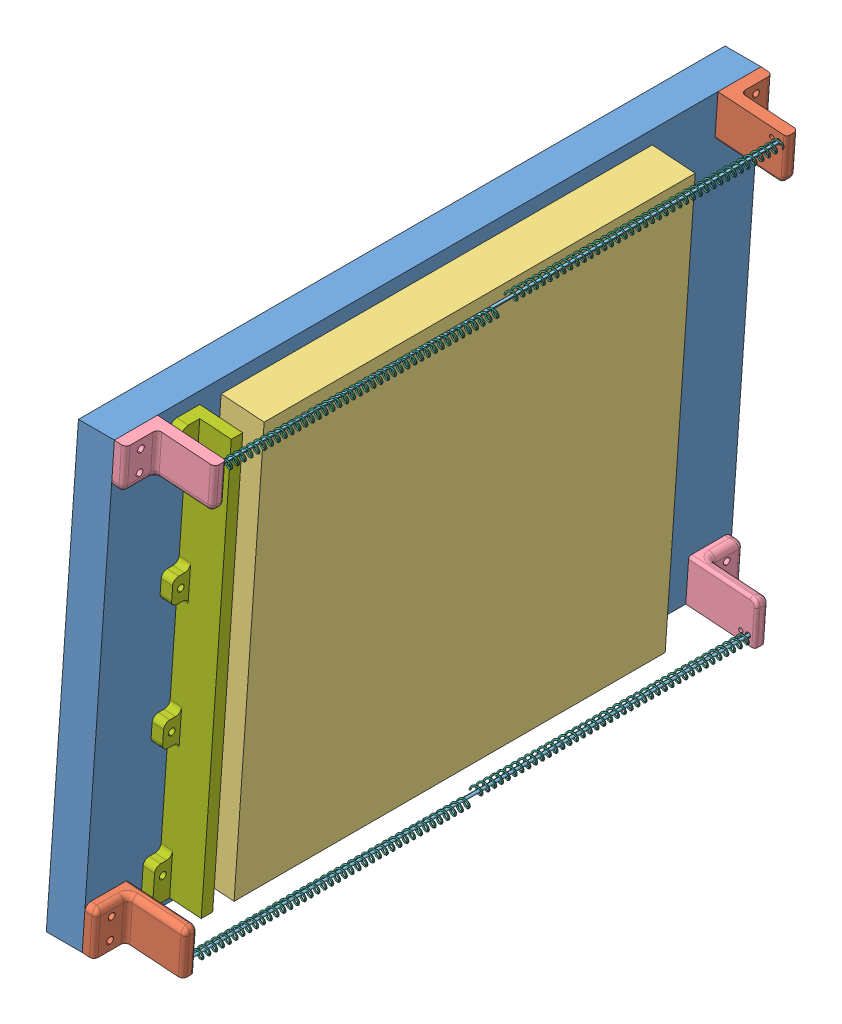
SolidWorks assembly Radiateur, configuration Default. Lengths in mm.
Overall size (95.68 323.35 450.01).
14 component instances, 7 part files, 0 mates.
Components (placement in the parent):
- Radiateur.STEP-1: Radiateur.STEP [Default] at origin size (95.68 323.35 450.01)
  - Mur_largeur.STEP-1: Mur_largeur.STEP [Default] at (-64.9032 -140.3514 -216.6004) size (47.38 320 450)
  - braquetterad2.STEP-1: braquetterad2.STEP [Default] at (-39.9032 -140.3514 233.3996) x (0 0 -1) z (-0.069756 -0.997564 0) size (30 48 30)
  - 05-Radiateur.STEP-1: 05-Radiateur.STEP [Default] at (-9.2242 -131.689 158.3996) x (0.069756 0.997564 0) z (0 0 1) size (300 30 300)
  - braquetterad1.STEP-1: braquetterad1.STEP [Default] at (-19.6193 149.7217 233.3996) x (0 0 -1) z (-0.069756 -0.997564 0) size (30 48 30)
  - braquetterad2.STEP-2: braquetterad2.STEP [Default] at (-17.5266 179.6486 -216.6004) x (0 0 1) z (0.069756 0.997564 0) size (30 48 30)
  - braquetterad1.STEP-2: braquetterad1.STEP [Default] at (-37.8105 -110.4245 -216.6004) x (0 0 1) z (0.069756 0.997564 0) size (30 48 30)
  - tigerad.STEP-1: tigerad.STEP [Default] at (24.9501 170.6637 -191.6004) x (-0.267506 0.963556 0) z (0.963556 0.267506 0) size (2 400 2)
  - tigerad.STEP-2: tigerad.STEP [Default] at (3.4106 -137.3656 208.3996) x (1 0 0) z (0 1 0) size (2 400 2)
  - Springs.STEP-1: Springs.STEP [Default] at (0.7048 -136.4477 4.1759) x (1 0 0) z (0 0.999962 -0.008727) size (7 191 8.08)
  - Springs.STEP-2: Springs.STEP [Default] at (22.024 170.9453 1.098) x (1 0 0) z (0 0.999962 -0.008727) size (7 191 8.08)
  - Springs.STEP-3: Springs.STEP [Default] at (24.2732 170.9212 201.9899) x (1 0 0) z (0 0.999962 -0.008727) size (7 191 8.08)
  - Springs.STEP-4: Springs.STEP [Default] at (2.2292 -136.5481 199.8891) x (1 0 0) z (0 0.999962 -0.008727) size (7 191 8.08)
  - rightshield.STEP-1: rightshield.STEP [Default] at (-39.0719 -128.4631 173.3565) x (0.997564 -0.069756 0) z (-0.069756 -0.997564 0) size (30 20 300)
